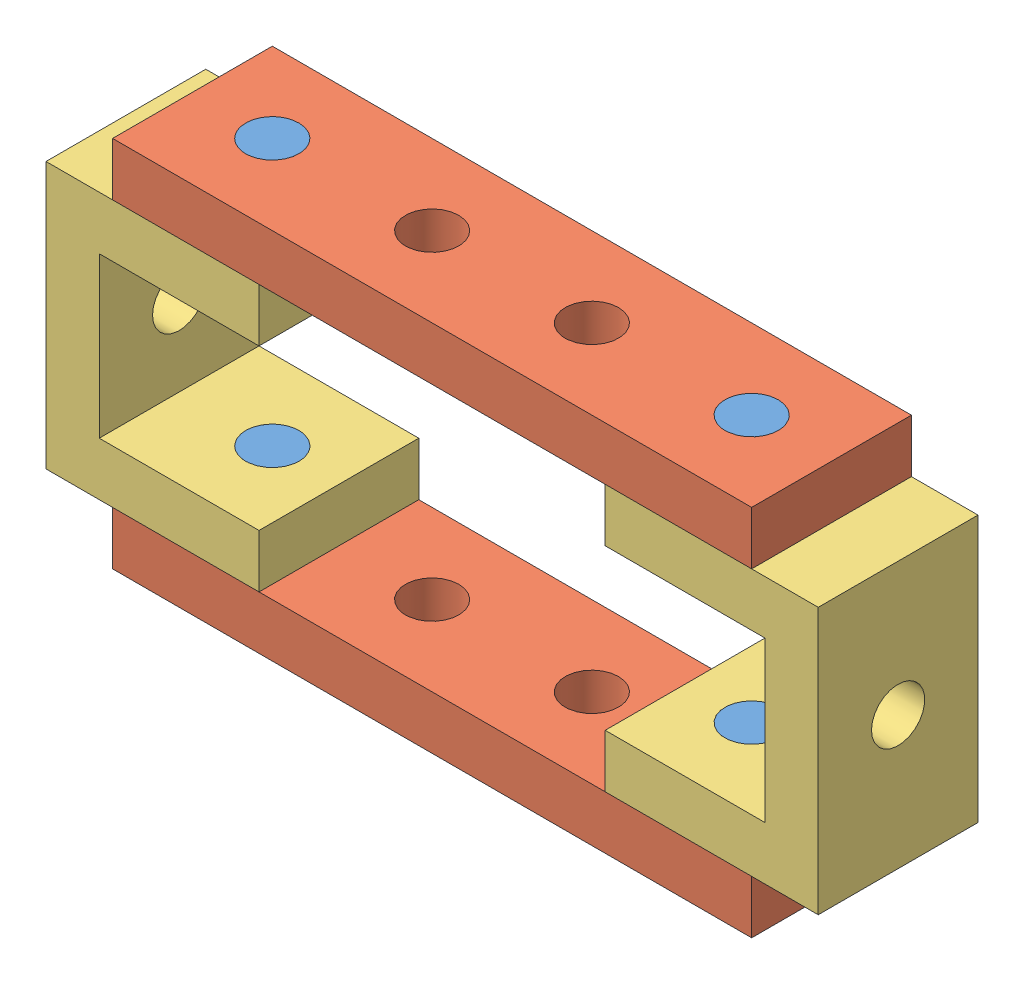
SolidWorks assembly Lecture5_practiceassembly_21010264, configuration Default. Lengths in mm.
Overall size (145 70 30).
8 component instances, 3 part files, 14 mates.
Components (placement in the parent):
- Lecture5_pin_21010264-2: Lecture5_pin_21010264 [Default] at (-127.0011 -122.8964 7.58) size (10 20 10)
- Lecture5_straight_21010264-2: Lecture5_straight_21010264 [Default] at (-142.0011 -122.8964 22.58) size (120 10 30)
- Lecture5_u_21010264-2: Lecture5_u_21010264 [Default] at (-154.5011 -112.8964 22.58) size (40 50 30)
- Lecture5_pin_21010264-3: Lecture5_pin_21010264 [Default] at (-127.0011 -72.8964 7.58) size (10 20 10)
- Lecture5_straight_21010264-3: Lecture5_straight_21010264 [Default] at (-142.0011 -62.8964 22.58) size (120 10 30)
- Lecture5_u_21010264-3: Lecture5_u_21010264 [Default] at (-9.5011 -62.8964 22.58) x (-1 0 0) z (0 0 1) size (40 50 30)
- Lecture5_pin_21010264-4: Lecture5_pin_21010264 [Default] at (-37.0011 -122.8964 7.58) size (10 20 10)
- Lecture5_pin_21010264-5: Lecture5_pin_21010264 [Default] at (-37.0011 -72.8964 7.58) size (10 20 10)
Mates (geometry in assembly coordinates):
- Concentric3: concentric aligned: cylinder of Lecture5_pin_21010264-2 through (-127.0011 -102.8964 7.58) axis (0 -1 0) radius 5; cylinder of Lecture5_u_21010264-2 through (-127.0011 -62.8964 7.58) axis (0 -1 0) radius 5
- Coincident4: coincident aligned: plane of Lecture5_pin_21010264-2 through (-127.0011 -102.8964 7.58) normal (0 1 0); plane of Lecture5_u_21010264-2 through (-114.5011 -102.8964 -11.42) normal (0 1 0)
- Coincident5: coincident aligned: plane of Lecture5_pin_21010264-2 through (-127.0011 -122.8964 7.58) normal (0 -1 0); plane of Lecture5_straight_21010264-2 through (-142.0011 -122.8964 22.58) normal (0 -1 0)
- Concentric4: concentric aligned: cylinder of Lecture5_pin_21010264-2 through (-127.0011 -102.8964 7.58) axis (0 -1 0) radius 5; cylinder of Lecture5_straight_21010264-2 through (-127.0011 -112.8964 7.58) axis (0 -1 0) radius 5
- Concentric5: concentric aligned: cylinder of Lecture5_u_21010264-2 through (-127.0011 -62.8964 7.58) axis (0 -1 0) radius 5; cylinder of Lecture5_pin_21010264-3 through (-127.0011 -52.8964 7.58) axis (0 -1 0) radius 5
- Coincident6: coincident aligned: plane of Lecture5_u_21010264-2 through (-114.5011 -72.8964 -11.42) normal (0 -1 0); plane of Lecture5_pin_21010264-3 through (-127.0011 -72.8964 7.58) normal (0 -1 0)
- Concentric6: concentric aligned: cylinder of Lecture5_pin_21010264-3 through (-127.0011 -52.8964 7.58) axis (0 -1 0) radius 5; cylinder of Lecture5_straight_21010264-3 through (-127.0011 -52.8964 7.58) axis (0 -1 0) radius 5
- Coincident7: coincident anti-aligned: plane of Lecture5_u_21010264-2 through (-154.5011 -62.8964 22.58) normal (0 1 0); plane of Lecture5_straight_21010264-3 through (-142.0011 -62.8964 22.58) normal (0 -1 0)
- Concentric7: concentric aligned: cylinder of Lecture5_straight_21010264-2 through (-37.0011 -112.8964 7.58) axis (0 -1 0) radius 5; cylinder of Lecture5_pin_21010264-4 through (-37.0011 -102.8964 7.58) axis (0 -1 0) radius 5
- Coincident8: coincident aligned: plane of Lecture5_straight_21010264-2 through (-142.0011 -122.8964 22.58) normal (0 -1 0); plane of Lecture5_pin_21010264-4 through (-37.0011 -122.8964 7.58) normal (0 -1 0)
- Concentric8: concentric aligned: cylinder of Lecture5_straight_21010264-3 through (-37.0011 -52.8964 7.58) axis (0 -1 0) radius 5; cylinder of Lecture5_pin_21010264-5 through (-37.0011 -52.8964 7.58) axis (0 -1 0) radius 5
- Coincident9: coincident aligned: plane of Lecture5_straight_21010264-3 through (-142.0011 -52.8964 22.58) normal (0 1 0); plane of Lecture5_pin_21010264-5 through (-37.0011 -52.8964 7.58) normal (0 1 0)
- Coincident10: coincident anti-aligned: plane of Lecture5_straight_21010264-2 through (-142.0011 -112.8964 22.58) normal (0 1 0); plane of Lecture5_u_21010264-3 through (-9.5011 -112.8964 22.58) normal (0 -1 0)
- Concentric9: concentric anti-aligned: cylinder of Lecture5_u_21010264-3 through (-37.0011 -112.8964 7.58) axis (0 1 0) radius 5; cylinder of Lecture5_pin_21010264-4 through (-37.0011 -102.8964 7.58) axis (0 -1 0) radius 5
